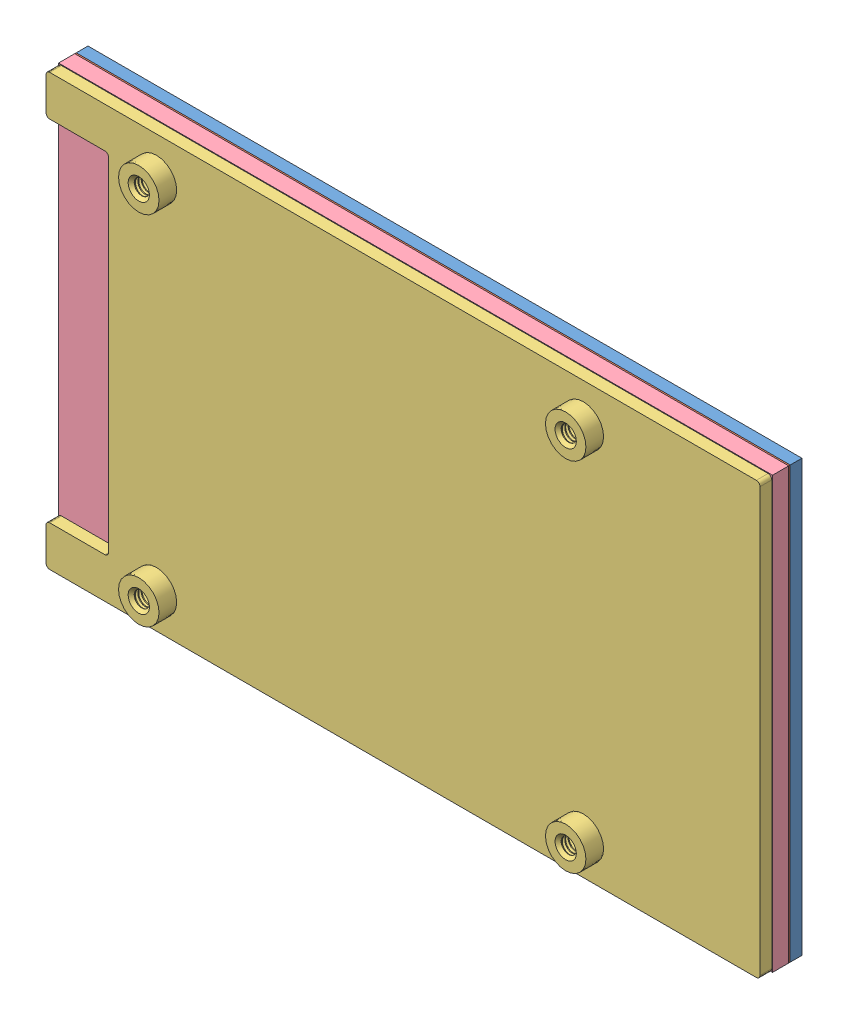
SolidWorks assembly HyperPixel 4, configuration Default. Lengths in mm.
Overall size (97 58.5 8.1).
10 component instances, 6 part files, 0 mates.
Components (placement in the parent):
- HyperPixel 4.stp-1: HyperPixel 4.stp [Default] at origin size (97 58.5 22.6)
  - Component1.stp-1: Component1.stp [Default] at origin size (97 58.5 1.6)
  - Component2.stp-1: Component2.stp [Default] at origin size (97 58.5 0.2)
  - PCB.stp-1: PCB.stp [Default] at origin size (97 58.5 4.04)
  - LCD.stp-1: LCD.stp [Default] at origin size (97 58.5 2.2)
  - Component5.stp-1: Component5.stp [Default] at origin size (51.4 5 4.7) (hidden)
  - Component6.stp-1: Component6.stp [Default] at origin size (5.5 5 18.08) (hidden)
  - Component6.stp-2: Component6.stp [Default] at (58 0 0) size (5.5 5 18.08) (hidden)
  - Component6.stp-3: Component6.stp [Default] at (0 48.5 0) size (5.5 5 18.08) (hidden)
  - Component6.stp-4: Component6.stp [Default] at (58 48.5 0) size (5.5 5 18.08) (hidden)
